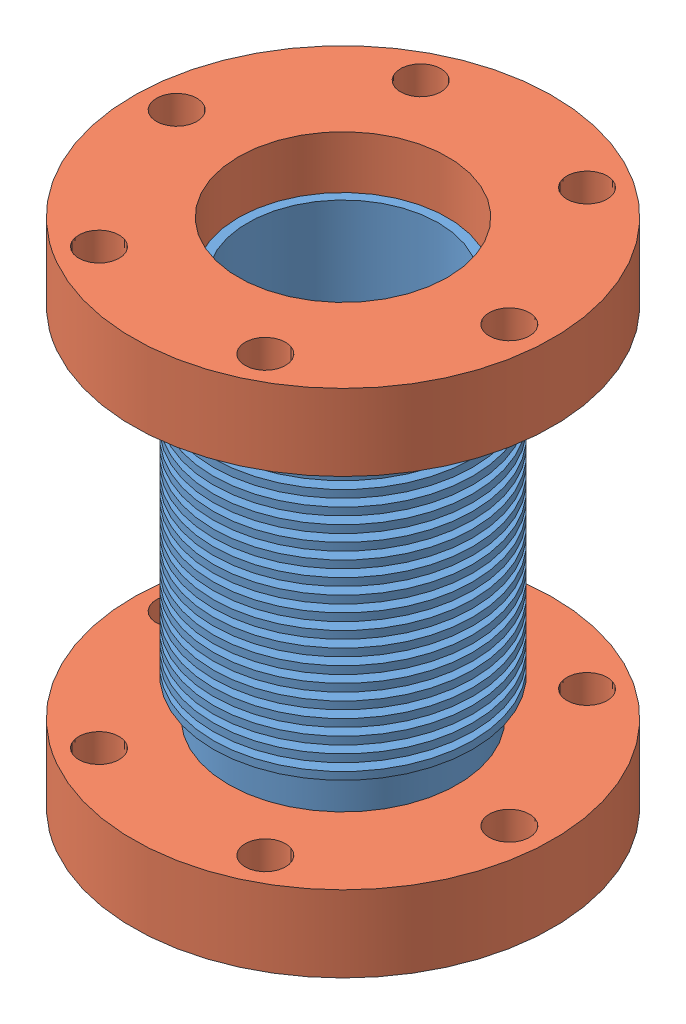
SolidWorks assembly Bellow_2.75in_CF, configuration Default. Lengths in mm.
Overall size (96.68 84.96 96.68).
3 component instances, 2 part files, 3 mates.
Components (placement in the parent):
- 2.75in_bellow_tube-1: 2.75in_bellow_tube [Default] at (-27.8121 6.8508 10.0217) size (43.18 63.5 43.18)
- 2.75in_CF_flange-1: 2.75in_CF_flange [Default] at (-27.8121 47.3621 10.0217) x (-0.837169 0 -0.546944) z (-0.546944 0 0.837169) size (69.85 12.7 69.85)
- 2.75in_CF_flange-2: 2.75in_CF_flange [Default] at (-27.8121 -24.8992 10.0217) x (-0.837169 0 -0.546944) z (-0.546944 0 0.837169) size (69.85 12.7 69.85)
Mates (geometry in assembly coordinates):
- Concentric1: concentric anti-aligned: circle of 2.75in_bellow_tube-1; circle of 2.75in_CF_flange-1
- Concentric2: concentric anti-aligned: circle of 2.75in_bellow_tube-1; circle of 2.75in_CF_flange-2
- Coincident1: coincident aligned: circle of 2.75in_bellow_tube-1; plane of 2.75in_CF_flange-2 through (-27.8121 -24.8992 10.0217) normal (0 1 0)
